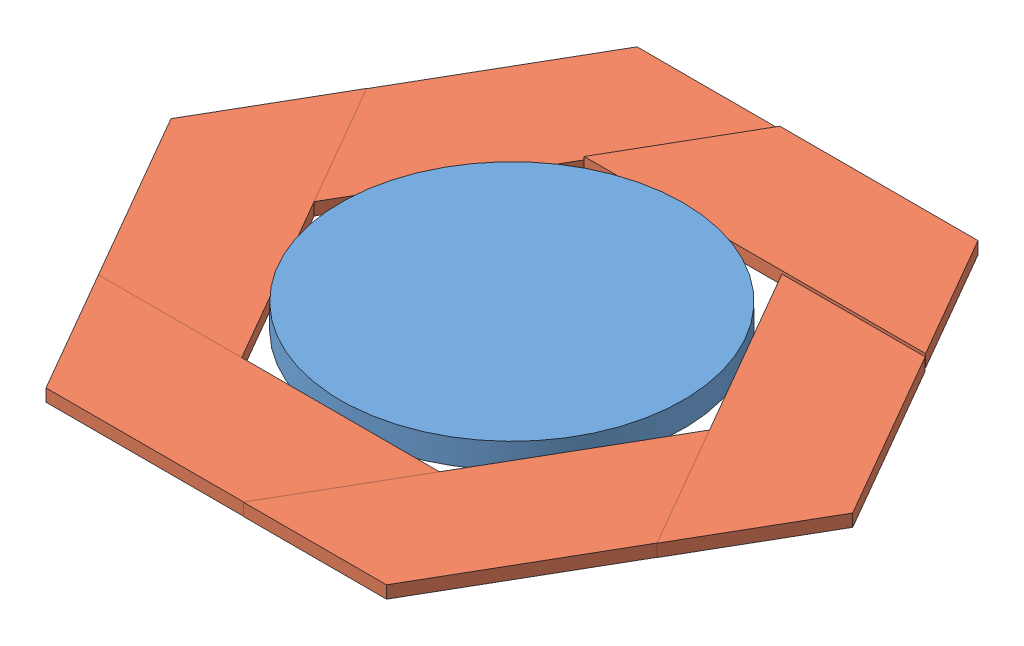
SolidWorks assembly КольцоСб, configuration По умолчанию. Lengths in mm.
Overall size (303.82 10 288.24).
7 component instances, 2 part files, 19 mates.
Components (placement in the parent):
- Круг138-1: Круг138 [По умолчанию] at (1.341 -4.851 138) size (138 10 138)
- Планка60-1: Планка60 [По умолчанию] at (-67.3637 -4.851 257) size (137.55 5 50)
- Планка60-2: Планка60 [По умолчанию] at (-136.1372 -4.851 137.8808) x (0.5 0 0.866025) z (-0.866025 0 0.5) size (137.55 5 50)
- Планка60-3: Планка60 [По умолчанию] at (-67.2949 -4.851 18.8808) x (-0.5 0 0.866025) z (-0.866025 0 -0.5) size (137.55 5 50)
- Планка60-4: Планка60 [По умолчанию] at (70.1833 -3.6616 19) x (-1 0 0) z (0 0 -1) size (137.55 5 50)
- Планка60-5: Планка60 [По умолчанию] at (138.8191 -4.851 138.1192) x (-0.5 0 -0.866025) z (0.866025 0 -0.5) size (137.55 5 50)
- Планка60-6: Планка60 [По умолчанию] at (69.9768 -4.851 257.1192) x (0.5 0 -0.866025) z (0.866025 0 0.5) size (137.55 5 50)
Mates (geometry in assembly coordinates):
- Совпадение1: coincident aligned: plane of Круг138-1 through (1.341 -4.851 138) normal (0 -1 0); plane of Планка60-1 through (-79.2592 -4.851 249.2877) normal (0 -1 0)
- Касательность1: tangent anti-aligned: cylinder of Круг138-1 through (1.341 5.149 138) axis (0 -1 0) radius 69; plane of Планка60-1 through (33.9936 0.149 210.7516) normal (0.103035 0 -0.994678)
- Совпадение2: coincident aligned: plane of Круг138-1 through (1.341 -4.851 138) normal (0 -1 0); plane of Планка60-2 through (-135.3933 -4.851 123.7164) normal (0 -1 0)
- Касательность2: tangent anti-aligned: cylinder of Круг138-1 through (1.341 5.149 138) axis (0 -1 0) radius 69; plane of Планка60-2 through (-45.3936 0.149 202.5282) normal (0.912933 0 -0.408108)
- Совпадение3: coincident anti-aligned: plane of Планка60-1 through (33.9936 0.149 210.7516) normal (0.103035 0 -0.994678); plane of Планка60-2 through (-102.8213 0.149 196.5795) normal (-0.103035 0 0.994678)
- Совпадение4: coincident aligned: plane of Планка60-1 through (-102.8213 0.149 196.5795) normal (-0.912933 0 0.408108); plane of Планка60-2 through (-135.3933 0.149 123.7164) normal (-0.912933 0 0.408108)
- Совпадение5: coincident aligned: plane of Круг138-1 through (1.341 -4.851 138) normal (0 -1 0); plane of Планка60-3 through (-54.6562 -4.851 12.4429) normal (0 -1 0)
- Касательность3: tangent anti-aligned: cylinder of Круг138-1 through (1.341 5.149 138) axis (0 -1 0) radius 69; plane of Планка60-3 through (-77.9093 0.149 129.7908) normal (0.809899 0 0.586569)
- Совпадение6: coincident anti-aligned: plane of Планка60-2 through (-45.3936 0.149 202.5282) normal (0.912933 0 -0.408108); plane of Планка60-3 through (-101.4715 0.149 77.0826) normal (-0.912933 0 0.408108)
- Параллельность1: parallel aligned: plane of Планка60-2 through (-101.5277 0.149 76.9569) normal (-0.809899 0 -0.586569); plane of Планка60-3 through (-54.6562 0.149 12.4429) normal (-0.809899 0 -0.586569)
- Совпадение8: coincident anti-aligned: plane of Планка60-3 through (-77.9093 0.149 129.7908) normal (0.809899 0 0.586569); plane of Планка60-4 through (-62.0246 1.3384 18.5031) normal (-0.809899 0 -0.586569)
- Касательность4: tangent anti-aligned: cylinder of Круг138-1 through (1.341 5.149 138) axis (0 -1 0) radius 69; plane of Планка60-4 through (-95.8902 1.3384 65.2626) normal (-0.103035 0 0.994678)
- Совпадение9: coincident aligned: plane of Круг138-1 through (1.341 -4.851 138) normal (0 -1 0); plane of Планка60-5 through (138.0752 -4.851 152.2836) normal (0 -1 0)
- Совпадение10: coincident anti-aligned: plane of Планка60-4 through (-95.8902 1.3384 65.2626) normal (-0.103035 0 0.994678); plane of Планка60-5 through (105.5032 0.149 79.4205) normal (0.103035 0 -0.994678)
- Касательность5: tangent anti-aligned: cylinder of Круг138-1 through (1.341 5.149 138) axis (0 -1 0) radius 69; plane of Планка60-5 through (48.0755 0.149 73.4718) normal (-0.912933 0 0.408108)
- Совпадение11: coincident anti-aligned: plane of Планка60-5 through (48.0755 0.149 73.4718) normal (-0.912933 0 0.408108); plane of Планка60-6 through (104.1534 0.149 198.9174) normal (0.912933 0 -0.408108)
- Совпадение12: coincident aligned: plane of Круг138-1 through (1.341 -4.851 138) normal (0 -1 0); plane of Планка60-6 through (57.3381 -4.851 263.5571) normal (0 -1 0)
- Касательность6: tangent anti-aligned: cylinder of Круг138-1 through (1.341 5.149 138) axis (0 -1 0) radius 69; plane of Планка60-6 through (80.5913 0.149 146.2092) normal (-0.809899 0 -0.586569)
- Параллельность4: parallel anti-aligned: plane of Планка60-4 through (70.1833 1.3384 19) normal (0 0 -1)
